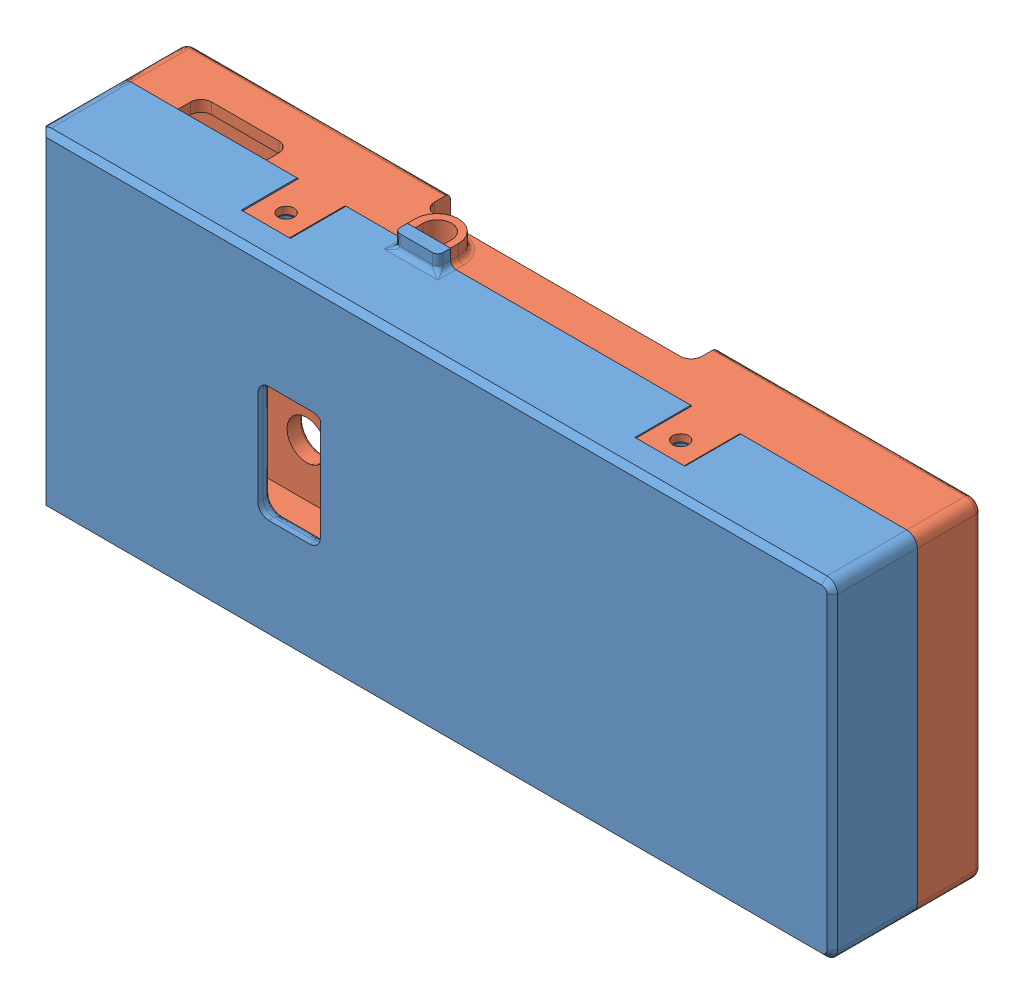
SolidWorks assembly 遥控器, configuration 默认. Lengths in mm.
Overall size (150.01 64.99 31).
3 component instances, 3 part files, 4 mates.
Components (placement in the parent):
- 底座-1: 底座 [默认] at (66.8169 -25.1724 150) size (150 64.99 16)
- 上盖-1: 上盖 [默认] at (38.6539 7.1279 137) x (0 1 0) z (0 0 -1) size (64.99 150.01 25.2)
- 开关-1: 开关 [默认] at (64.912 16.0373 134) x (-1 0 0) z (0 0 -1) size (10.62 7.17 12)
Mates (geometry in assembly coordinates):
- 重合1: coincident anti-aligned: plane of 底座-1 through (66.8169 -25.1724 137) normal (0 0 -1); plane of 上盖-1 through (38.6539 7.1279 137) normal (0 0 1)
- 重合2: coincident aligned: plane of 底座-1 through (-67.4741 -35.2333 -38.3083) normal (0 -1 0); plane of 上盖-1 through (82.5259 -35.2333 128) normal (0 -1 0)
- 重合4: coincident aligned: plane of 底座-1 through (82.5259 -35.2333 -38.3083) normal (1 0 0); plane of 上盖-1 through (82.5259 -35.2333 128) normal (1 0 0)
- 重合7: coincident anti-aligned: plane of 上盖-1 through (38.6539 7.1279 128) normal (0 0 1); plane of 开关-1 through (64.912 16.0373 128) normal (0 0 -1)
